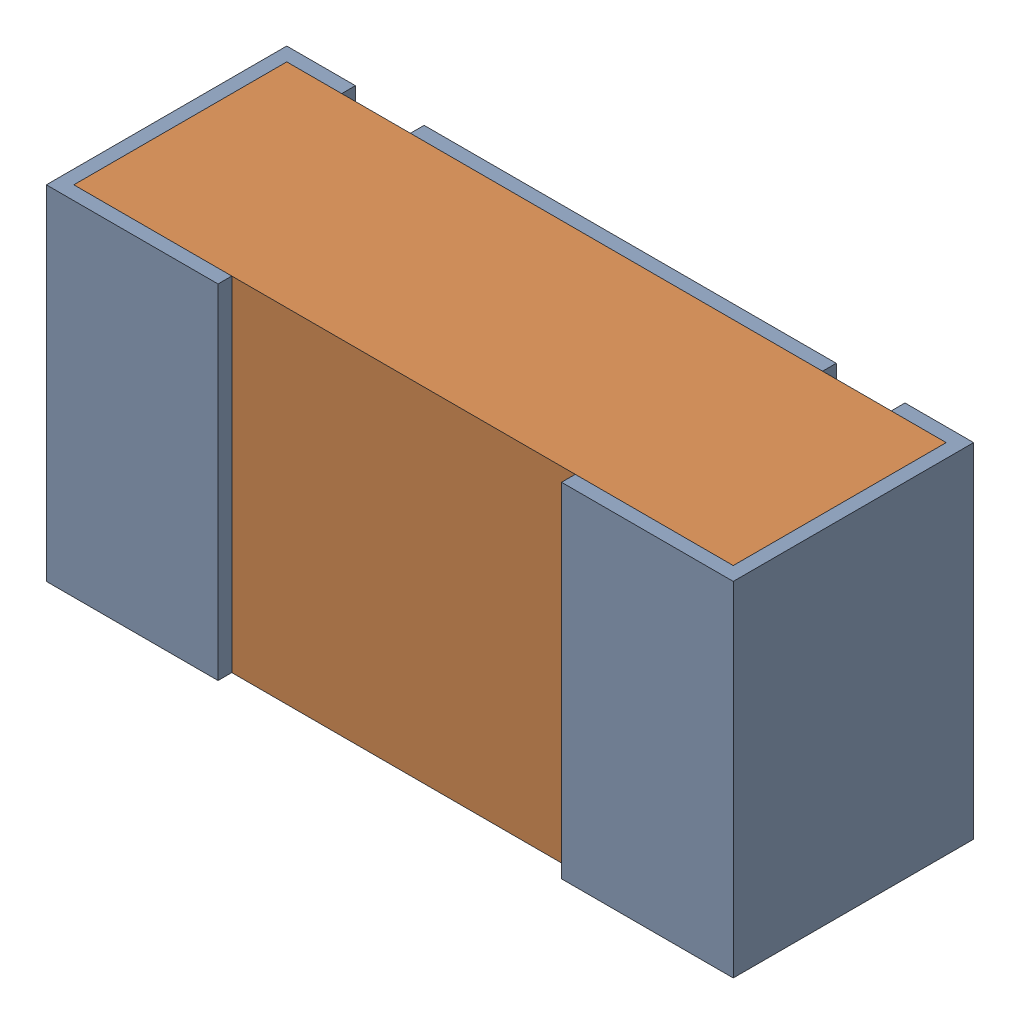
SolidWorks assembly R20, configuration Default. Lengths in mm.
Overall size (1 0.5 0.35).
3 component instances, 2 part files, 0 mates.
Components (placement in the parent):
- R20-subassembly-1-1: R20-subassembly-1 [Default] at (1.4251 5.75 -1.6307) x (-1 0 0) z (0 -1 0) size (1 0.35 0.5)
  - 0402 resistor-1: 0402 resistor [Default] at origin size (1 0.35 0.5)
  - 0402 resistor-1-1: 0402 resistor-1 [Default] at origin size (0.96 0.31 0.5)
